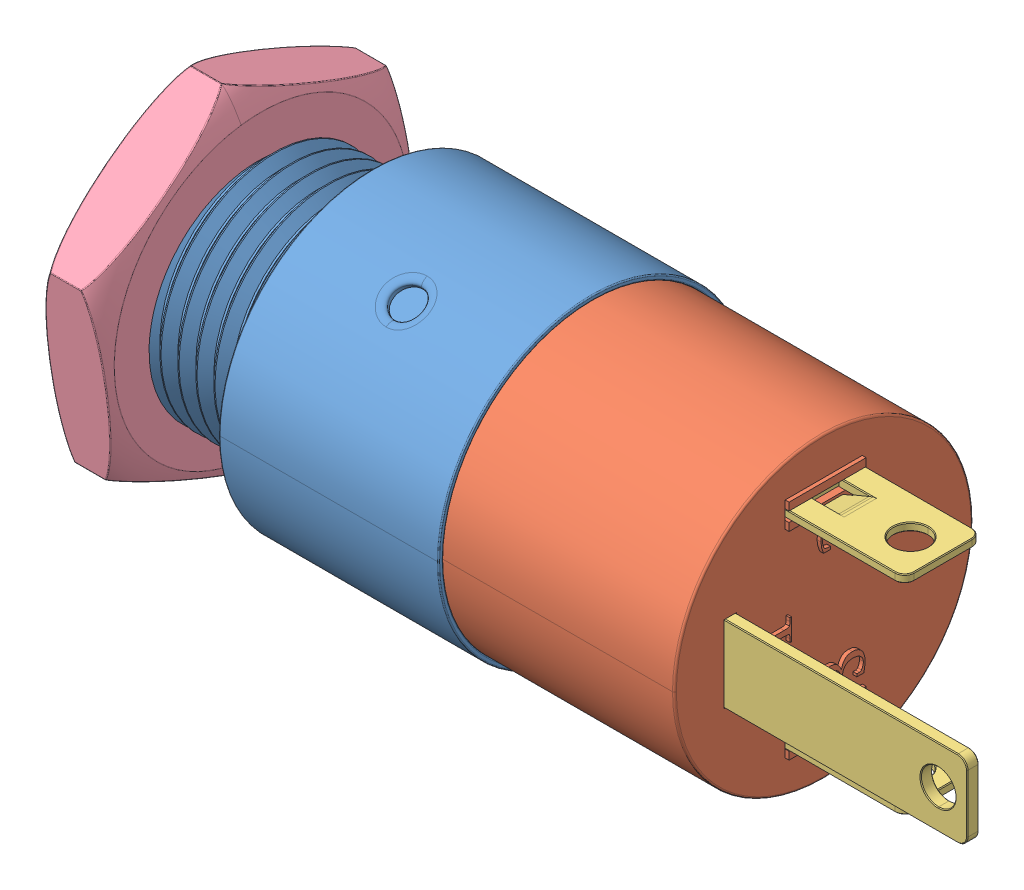
SolidWorks assembly 3.5mmJack, configuration Default. Lengths in mm.
Overall size (22.53 10.42 10.41).
4 component instances, 4 part files, 2 mates.
Components (placement in the parent):
- front metal(2)-1: front metal(2) [front metal(2)] at (4 4 -0.4844) x (0 1 0) z (0 0 1) size (8 10.2 8)
- mid plastic(2)-1: mid plastic(2) [mid plastic(2)] at (4 4 -0.4844) x (0 1 0) z (0 0 1) size (7.75 8.1 7.75)
- pin(2)-1: pin(2) [pin(2)] at (4 4 -0.4844) x (0 1 0) z (0 0 1) size (5.4 8.3 3.58)
- nut________(2)-1: nut________(2) [nut________(2)] at (1.1 4.0027 -0.4876) x (0 -0.99048 -0.137658) z (0 0.137658 -0.99048) size (9.24 1.66 9.22)
Mates (geometry in assembly coordinates):
- Coincident1: coincident aligned: plane of front metal(2)-1 through (-0.5 4 -0.4844) normal (-1 0 0); plane of nut________(2)-1 through (-0.5 3.0383 0.0871) normal (-1 0 0)
- Tangent3: tangent: curve of nut________(2)-1; face of nut________(2)-1
